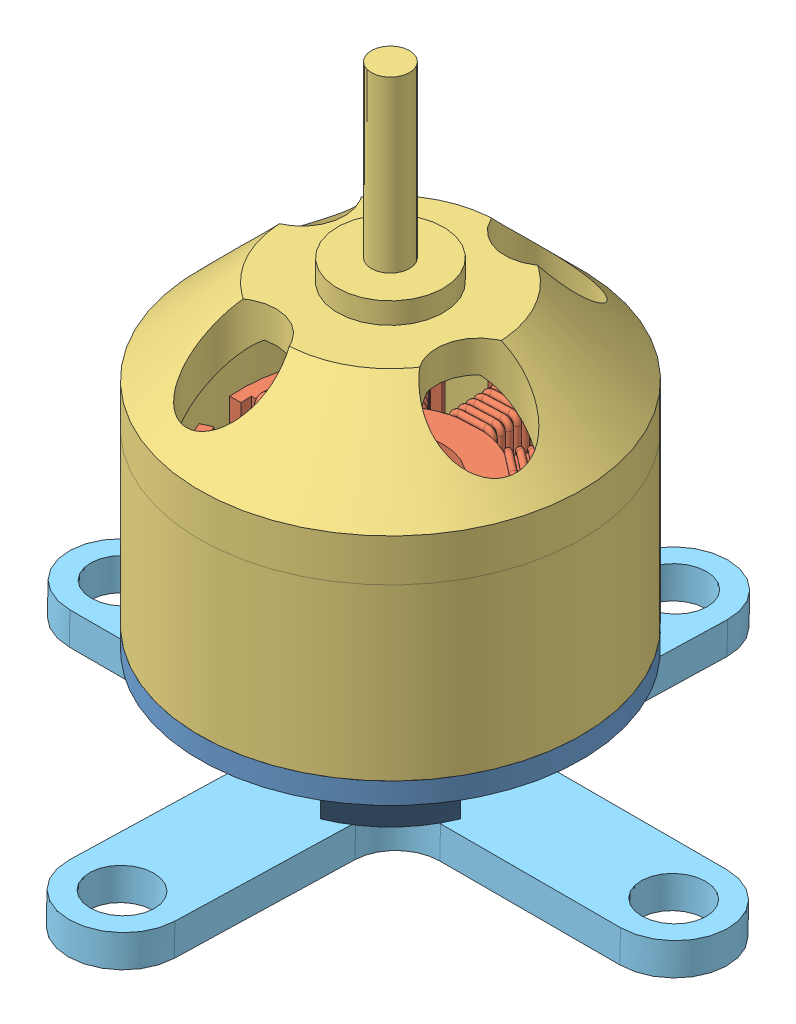
SolidWorks assembly Assem1, configuration Default. Lengths in mm.
Overall size (31.07 29.45 31.09).
5 component instances, 5 part files, 8 mates.
Components (placement in the parent):
- alt_gövde-3: alt_gövde [Varsayılan] at (2.5363 9.3332 14.7058) size (18 4 18)
- bobin_1-3: bobin_1 [Varsayılan] at (2.5363 11.4582 14.7058) x (0.999173 0 -0.040654) z (0 1 0) size (14.06 14 8.53)
- gövde-3: gövde [Varsayılan] at (2.5363 21.3332 14.7058) x (-0.963239 0 -0.268646) z (0.268646 0 -0.963239) size (18 28 18)
- rulman_iç-3: rulman_iç [Varsayılan] at (2.5363 8.8332 14.7058) size (3 1 3)
- tutucu-3: tutucu [Varsayılan] at (2.8803 7.311 14.7113) x (0.999996 0.002147 0.002093) z (-0.002093 0.99968 -0.025202) size (31 31 1.5)
Mates (geometry in assembly coordinates):
- Concentric1: concentric: cylinder of assembly; cylinder of assembly; cylinder of gövde-3 through (2.5363 8.3332 14.7058) axis (0 1 0) radius 0.9; cylinder of rulman_iç-3 through (2.5363 8.3332 14.7058) axis (0 1 0) radius 0.9
- Concentric2: concentric: cylinder of assembly; cylinder of assembly; cylinder of bobin_1-3 through (2.5363 19.4582 14.7058) axis (0 -1 0) radius 7.0295; cylinder of gövde-3 through (2.5363 13.3332 14.7058) axis (0 1 0) radius 8.5
- Coincident4: coincident: plane of assembly; plane of assembly; plane of alt_gövde-3 through (2.5363 13.3332 14.7058) normal (0 1 0); plane of gövde-3 through (2.5363 13.3332 14.7058) normal (0 -1 0)
- Concentric4: concentric: cylinder of assembly; cylinder of assembly; cylinder of alt_gövde-3 through (2.5363 12.3332 14.7058) axis (0 -1 0) radius 2.5; cylinder of gövde-3 through (2.5363 8.3332 14.7058) axis (0 1 0) radius 0.9
- Concentric5: concentric: cylinder of assembly; cylinder of assembly; cylinder of alt_gövde-3 through (2.5363 12.3332 14.7058) axis (0 -1 0) radius 2.5; cylinder of rulman_iç-3 through (2.5363 8.8332 14.7058) axis (0 -1 0) radius 1.5
- Parallel4: parallel: cylinder of assembly; cylinder of assembly; cylinder of gövde-3 through (2.5363 8.3332 14.7058) axis (0 1 0) radius 0.9; cylinder of rulman_iç-3 through (2.5363 8.8332 14.7058) axis (0 -1 0) radius 1.5
- Concentric8: concentric: cylinder of assembly; cylinder of assembly; cylinder of bobin_1-3 through (2.5363 19.4582 14.7058) axis (0 -1 0) radius 7.0295; cylinder of gövde-3 through (2.5363 13.3332 14.7058) axis (0 1 0) radius 8.5
- Tangent2: tangent: circle of assembly; plane of assembly; circle of gövde-3; plane of tutucu-3 through (2.8782 8.3107 14.6861) normal (-0.002093 0.99968 -0.025202)
